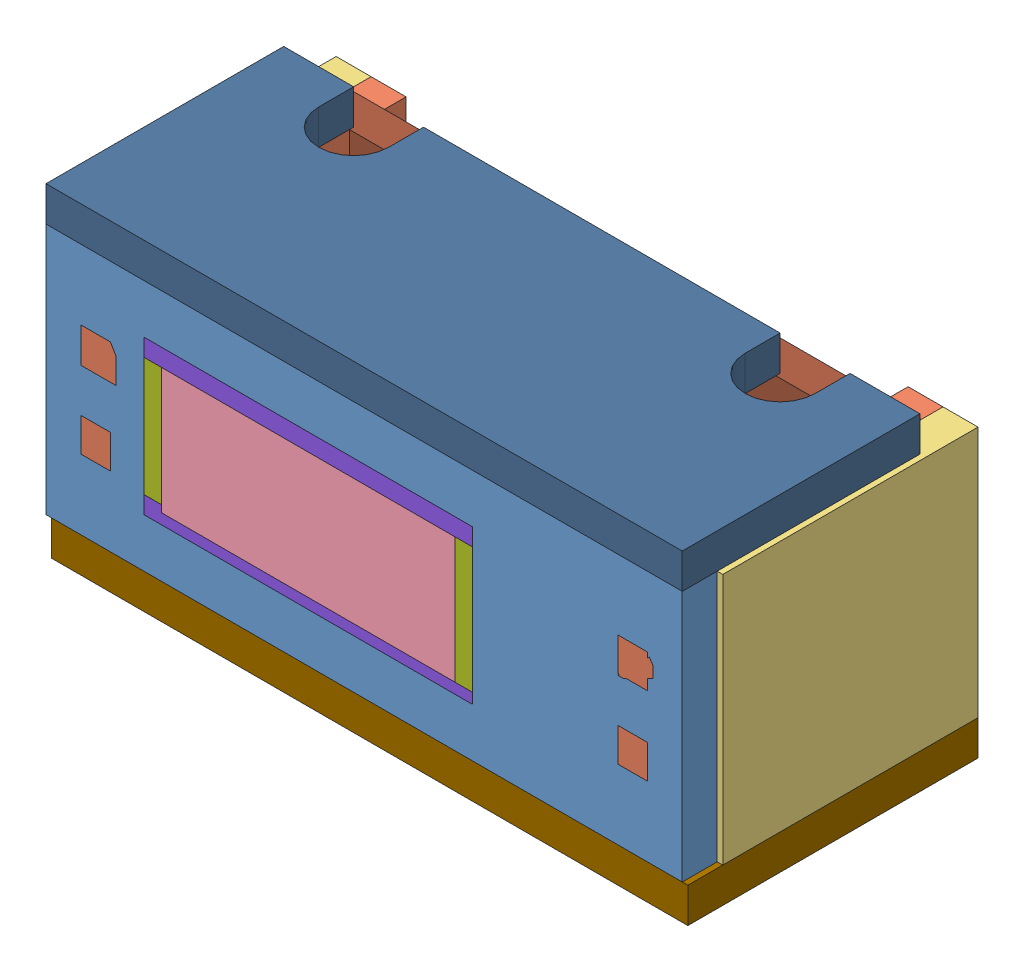
SolidWorks assembly Current Display Holding Box, configuration Default. Lengths in mm.
Overall size (116.59 70.48 52.7).
16 component instances, 11 part files, 36 mates.
Components (placement in the parent):
- Current Display Holding Box - Front-1: Current Display Holding Box - Front [Default] at (-32.0776 17.727 1.7084) size (115.57 45.72 6.35)
- Current Display Holding Box - Side-1: Current Display Holding Box - Side [Default] at (-83.5126 -5.133 8.0584) size (6.35 45.72 52.7)
- Current Display Holding Box - Side outside layer-1: Current Display Holding Box - Side outside layer [Default] at (-89.8626 -5.133 1.7084) size (6.35 45.72 46.35)
- Current Display Holding Box - Side-2: Current Display Holding Box - Side [Default] at (14.0234 -5.133 8.0584) size (6.35 45.72 52.7)
- Current Display Holding Box - Side outside layer-2: Current Display Holding Box - Side outside layer [Default] at (20.3734 -5.133 1.7084) size (6.35 45.72 46.35)
- Current Display Complete - simple-1: Current Display Complete - simple [Default] at (21.467 -0.8618 -20.0911) size (83.82 52.07 37.85)
  - Current Display-1: Current Display [Default] at (-90.3747 6.5238 14.6875) size (53.34 22.86 13.46)
  - Current Display Circuit Board-1: Current Display Circuit Board [Default] at (-95.4162 7.7938 3.0035) size (83.82 20.32 24.38)
  - Power Plug-1: Power Plug [Default] at (-78.0172 -22.6862 9.6075) x (-0.002337 0 0.999997) z (0 1 0) size (10.16 10.16 50.8)
- Foam - vertial-1: Foam - vertial [Default] at (-72.0826 5.662 8.0584) size (3.17 22.86 12.7)
- Foam - horizontal-1: Foam - horizontal [Default] at (-72.0826 28.522 8.0584) size (59.69 3.17 12.7)
- Foam - vertial-2: Foam - vertial [Default] at (-15.5676 5.662 8.0584) size (3.17 22.86 12.7)
- Foam - horizontal-2: Foam - horizontal [Default] at (-72.0826 3.757 8.0584) size (59.69 3.17 12.7)
- Current Display Holding Box - Bottom-4: Current Display Holding Box - Bottom [Default] at (-88.8466 -11.483 8.0584) size (115.57 6.35 52.7)
- Current Display Holding Box - Top v3-1: Current Display Holding Box - Top v3 [Default] at (-89.8626 40.587 8.0584) size (115.57 6.35 43.18)
- Current Display Holding Box - Back-1: Current Display Holding Box - Back [Default] at (-83.5126 1.217 -40.7096) size (102.87 45.72 6.35)
Mates (geometry in assembly coordinates):
- Coincident1: coincident anti-aligned: plane of Current Display Holding Box - Side-1 through (-83.5126 -5.133 8.0584) normal (-1 0 0); plane of Current Display Holding Box - Side outside layer-1 through (-83.5126 -5.133 1.7084) normal (1 0 0)
- Coincident2: coincident aligned: plane of Current Display Holding Box - Side-1 through (-83.5126 40.587 1.7084) normal (0 0 1); plane of Current Display Holding Box - Side outside layer-1 through (-83.5126 -5.133 1.7084) normal (0 0 1)
- Coincident3: coincident aligned: plane of Current Display Holding Box - Side-1 through (-77.1626 40.587 8.0584) normal (0 1 0); plane of Current Display Holding Box - Side outside layer-1 through (-83.5126 40.587 1.7084) normal (0 1 0)
- Coincident4: coincident anti-aligned: plane of Current Display Holding Box - Side-2 through (20.3734 -5.133 8.0584) normal (1 0 0); plane of Current Display Holding Box - Side outside layer-2 through (20.3734 -5.133 1.7084) normal (-1 0 0)
- Coincident5: coincident aligned: plane of Current Display Holding Box - Side-2 through (20.3734 40.587 8.0584) normal (0 1 0); plane of Current Display Holding Box - Side outside layer-2 through (26.7234 40.587 1.7084) normal (0 1 0)
- Coincident6: coincident aligned: plane of Current Display Holding Box - Side-2 through (14.0234 40.587 1.7084) normal (0 0 1); plane of Current Display Holding Box - Side outside layer-2 through (26.7234 -5.133 1.7084) normal (0 0 1)
- Coincident7: coincident anti-aligned: plane of Current Display Holding Box - Front-1 through (-83.5126 27.887 1.7084) normal (0 -1 0); plane of Current Display Holding Box - Side-1 through (-83.5126 27.887 8.0584) normal (0 1 0)
- Coincident8: coincident anti-aligned: plane of Current Display Holding Box - Front-1 through (-83.5126 27.887 1.7084) normal (1 0 0); plane of Current Display Holding Box - Side-1 through (-83.5126 -5.133 8.0584) normal (-1 0 0)
- Coincident9: coincident aligned: plane of Current Display Holding Box - Front-1 through (-32.0776 17.727 8.0584) normal (0 0 1); plane of Current Display Holding Box - Side-1 through (-77.1626 -5.133 8.0584) normal (0 0 1)
- Coincident10: coincident aligned: plane of Current Display Holding Box - Front-1 through (-32.0776 17.727 8.0584) normal (0 0 1); plane of Current Display Holding Box - Side-2 through (20.3734 -5.133 8.0584) normal (0 0 1)
- Coincident11: coincident anti-aligned: plane of Current Display Holding Box - Front-1 through (19.3574 27.887 1.7084) normal (0 -1 0); plane of Current Display Holding Box - Side-2 through (14.0234 27.887 8.0584) normal (0 1 0)
- Coincident12: coincident anti-aligned: plane of Current Display Holding Box - Front-1 through (14.0234 27.887 1.7084) normal (1 0 0); plane of Current Display Holding Box - Side-2 through (14.0234 -5.133 8.0584) normal (-1 0 0)
- Coincident13: coincident anti-aligned: plane of Current Display Holding Box - Front-1 through (-72.0826 3.757 1.7084) normal (1 0 0); plane of Foam - vertial-1 through (-72.0826 5.662 8.0584) normal (-1 0 0)
- Coincident14: coincident aligned: plane of Current Display Holding Box - Front-1 through (-32.0776 17.727 8.0584) normal (0 0 1); plane of Foam - vertial-1 through (-68.9076 5.662 8.0584) normal (0 0 1)
- Coincident15: coincident anti-aligned: plane of Current Display Holding Box - Front-1 through (-72.0826 31.697 1.7084) normal (0 -1 0); plane of Foam - horizontal-1 through (-72.0826 31.697 8.0584) normal (0 1 0)
- Coincident16: coincident aligned: plane of Current Display Holding Box - Front-1 through (-32.0776 17.727 8.0584) normal (0 0 1); plane of Foam - horizontal-1 through (-72.0826 31.697 8.0584) normal (0 0 1)
- Coincident17: coincident anti-aligned: plane of Current Display Holding Box - Front-1 through (-72.0826 3.757 1.7084) normal (1 0 0); plane of Foam - horizontal-1 through (-72.0826 31.697 8.0584) normal (-1 0 0)
- Coincident18: coincident anti-aligned: plane of Foam - vertial-1 through (-68.9076 28.522 8.0584) normal (0 1 0); plane of Foam - horizontal-1 through (-72.0826 28.522 8.0584) normal (0 -1 0)
- Coincident19: coincident anti-aligned: plane of Current Display Holding Box - Front-1 through (-12.3926 3.757 1.7084) normal (-1 0 0); plane of Foam - vertial-2 through (-12.3926 5.662 8.0584) normal (1 0 0)
- Coincident20: coincident anti-aligned: plane of Foam - horizontal-1 through (-72.0826 28.522 8.0584) normal (0 -1 0); plane of Foam - vertial-2 through (-12.3926 28.522 8.0584) normal (0 1 0)
- Coincident21: coincident anti-aligned: plane of Current Display Holding Box - Front-1 through (-72.0826 3.757 1.7084) normal (0 1 0); plane of Foam - horizontal-2 through (-72.0826 3.757 8.0584) normal (0 -1 0)
- Coincident22: coincident aligned: plane of Current Display Holding Box - Front-1 through (-32.0776 17.727 8.0584) normal (0 0 1); plane of Foam - horizontal-2 through (-72.0826 6.932 8.0584) normal (0 0 1)
- Coincident23: coincident anti-aligned: plane of Current Display Holding Box - Front-1 through (-72.0826 3.757 1.7084) normal (1 0 0); plane of Foam - horizontal-2 through (-72.0826 6.932 8.0584) normal (-1 0 0)
- Coincident24: coincident aligned: plane of Current Display Holding Box - Front-1 through (-32.0776 17.727 8.0584) normal (0 0 1); plane of Foam - vertial-2 through (-12.3926 5.662 8.0584) normal (0 0 1)
- Coincident25: coincident aligned: plane of Current Display Holding Box - Front-1 through (-32.0776 17.727 8.0584) normal (0 0 1); plane of Current Display Complete - simple-1/Current Display-1 through (-68.9076 5.662 8.0584) normal (0 0 1)
- Coincident26: coincident anti-aligned: plane of Current Display Complete - simple-1/Current Display-1 through (-68.9076 28.522 8.0584) normal (0 1 0); plane of Foam - horizontal-1 through (-72.0826 28.522 8.0584) normal (0 -1 0)
- Coincident27: coincident anti-aligned: plane of Current Display Complete - simple-1/Current Display-1 through (-68.9076 5.662 8.0584) normal (-1 0 0); plane of Foam - vertial-1 through (-68.9076 5.662 8.0584) normal (1 0 0)
- Coincident36: coincident aligned: plane of Current Display Holding Box - Front-1 through (-32.0776 17.727 8.0584) normal (0 0 1); plane of Current Display Holding Box - Bottom-4 through (-88.8466 -5.133 8.0584) normal (0 0 1)
- Coincident37: coincident aligned: plane of Current Display Holding Box - Side outside layer-2 through (26.7234 -5.133 1.7084) normal (1 0 0); plane of Current Display Holding Box - Bottom-4 through (26.7234 -5.133 8.0584) normal (1 0 0)
- Coincident38: coincident anti-aligned: plane of Current Display Holding Box - Front-1 through (-89.8626 -5.133 8.0584) normal (0 -1 0); plane of Current Display Holding Box - Bottom-4 through (-88.8466 -5.133 8.0584) normal (0 1 0)
- Coincident39: coincident aligned: plane of Current Display Holding Box - Front-1 through (-32.0776 17.727 8.0584) normal (0 0 1); plane of Current Display Holding Box - Top v3-1 through (-89.8626 46.937 8.0584) normal (0 0 1)
- Coincident40: coincident aligned: plane of Current Display Holding Box - Side outside layer-1 through (-89.8626 -5.133 1.7084) normal (-1 0 0); plane of Current Display Holding Box - Top v3-1 through (-89.8626 46.937 8.0584) normal (-1 0 0)
- Coincident41: coincident anti-aligned: plane of Current Display Holding Box - Front-1 through (-89.8626 40.587 8.0584) normal (0 1 0); plane of Current Display Holding Box - Top v3-1 through (-89.8626 40.587 8.0584) normal (0 -1 0)
- Coincident42: coincident anti-aligned: plane of Current Display Holding Box - Side outside layer-1 through (-83.5126 -5.133 1.7084) normal (1 0 0); plane of Current Display Holding Box - Back-1 through (-83.5126 1.217 -34.3596) normal (-1 0 0)
- Coincident43: coincident anti-aligned: plane of Current Display Holding Box - Side-1 through (-83.5126 40.587 -40.7096) normal (0 0 1); plane of Current Display Holding Box - Back-1 through (-83.5126 1.217 -40.7096) normal (0 0 -1)
- Coincident46: coincident anti-aligned: plane of Current Display Holding Box - Side-2 through (14.0234 1.217 -35.1216) normal (0 1 0); plane of Current Display Holding Box - Back-1 through (6.6574 1.217 -34.3596) normal (0 -1 0)
